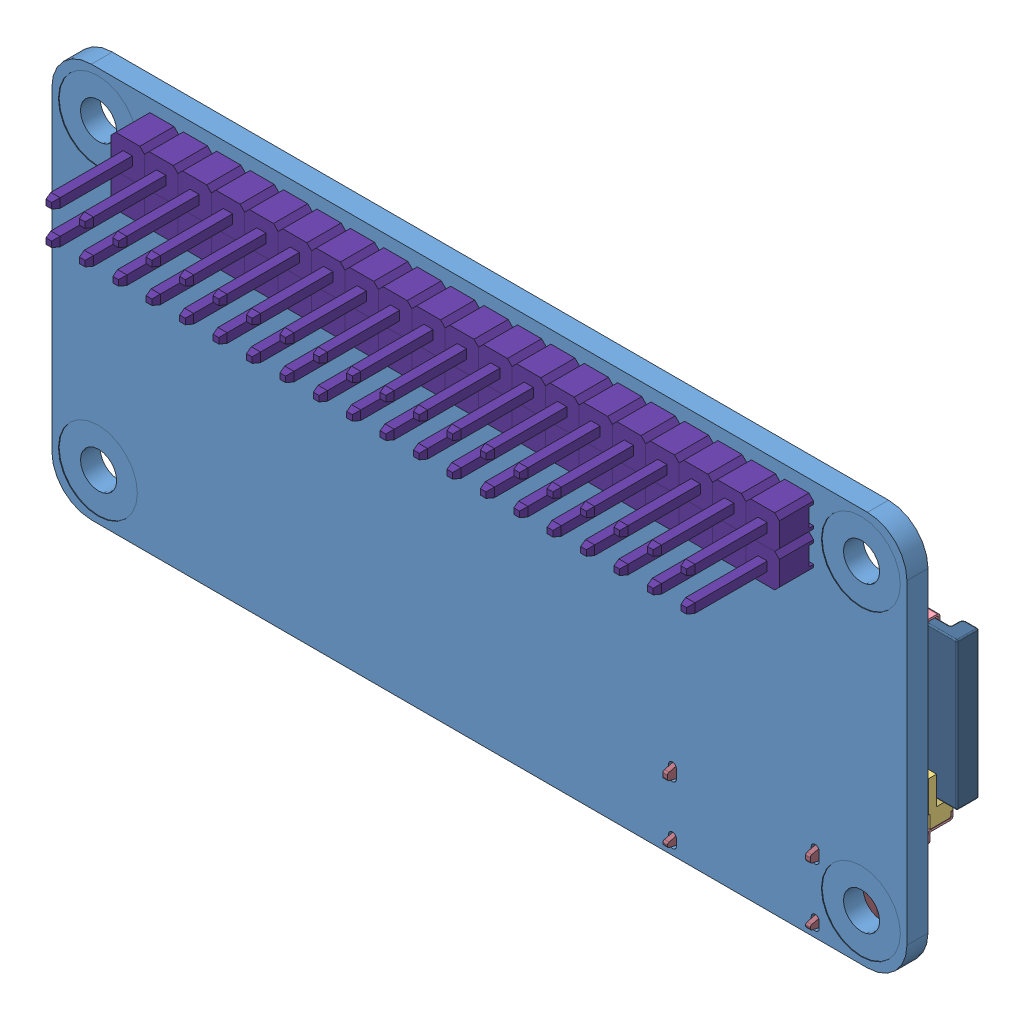
SolidWorks assembly rpi-zero-with-pin-header, configuration Default. Lengths in mm.
Overall size (67.36 31 13.5).
82 component instances, 17 part files, 6 mates.
Components (placement in the parent):
- rpi-zero-1: rpi-zero [Default] at (32.5 -26.5 -2.6) x (-1 0 0) z (0 0 -1) size (67.36 31 5.45)
  - rpi-zero-board-2: rpi-zero-board [Default] at (32.5 15 0) size (65 30 1.65)
  - rpi-zero-pin-header-pad-41: rpi-zero-pin-header-pad [Default] at (8.37 27.77 0.8) size (1.8 1.8 1.7)
  - rpi-zero-micro-sd-slot.step-1: rpi-zero-micro-sd-slot.step [Default] at (7.6 15.665 1.65) x (0 1 0) z (1 0 0) size (14.1 1.9 15.45)
    - microSD_Body.step-1: microSD_Body.step [Default] at origin size (14.1 1.85 15.2)
    - microSD_Cover.step-1: microSD_Cover.step [Default] at (0 1.7 0) x (1 0 0) z (0 0 -1) size (13.95 1.9 15.2)
    - microSD_Card_Detect.step-1: microSD_Card_Detect.step [Default] at (4.99 -0.05 7.4) size (4.45 1.9 2.05)
    - microSD_Pin_11.15.step-1: microSD_Pin_11.15.step [Default] at (5.725 0 -2) x (0 0 1) z (-1 0 0) size (7.35 1.18 0.6)
    - microSD_Pin_11.15.step-2: microSD_Pin_11.15.step [Default] at (4.625 0 -2) x (0 0 1) z (-1 0 0) size (7.35 1.18 0.6)
    - microSD_Pin_11.35.step-1: microSD_Pin_11.35.step [Default] at (3.525 0 -2) x (0 0 1) z (-1 0 0) size (7.35 1.18 0.6)
    - microSD_Pin_11.15.step-3: microSD_Pin_11.15.step [Default] at (2.425 0 -2) x (0 0 1) z (-1 0 0) size (7.35 1.18 0.6)
    - microSD_Pin_11.35.step-2: microSD_Pin_11.35.step [Default] at (1.325 0 -2) x (0 0 1) z (-1 0 0) size (7.35 1.18 0.6)
    - microSD_Pin_11.15.step-4: microSD_Pin_11.15.step [Default] at (0.225 0 -2) x (0 0 1) z (-1 0 0) size (7.35 1.18 0.6)
    - microSD_Pin_10.75.step-1: microSD_Pin_10.75.step [Default] at (-0.875 0 -2) x (0 0 1) z (-1 0 0) size (7.25 1.18 0.6)
    - microSD_Pin_11.15.step-5: microSD_Pin_11.15.step [Default] at (-1.975 0 -2) x (0 0 1) z (-1 0 0) size (7.35 1.18 0.6)
  - rpi-zero-fpc-connector.stp-1: rpi-zero-fpc-connector.stp [Default] at (61.5 15 1.61) x (0 1 0) z (1 0 0) size (17.6 2.04 5.2)
  - rpi-zero-micro-sd.stp-3: rpi-zero-micro-sd.stp [Default] at (6.17 16.9 2.45) x (1 0 0) z (0 -1 0) size (15.06 1.66 11.19)
  - rpi-zero-pin-header-pad-42: rpi-zero-pin-header-pad [Default] at (8.37 25.23 0.8) size (1.8 1.8 1.7)
  - rpi-zero-pin-header-pad-43: rpi-zero-pin-header-pad [Default] at (10.91 27.77 0.8) size (1.8 1.8 1.7)
  - rpi-zero-pin-header-pad-44: rpi-zero-pin-header-pad [Default] at (10.91 25.23 0.8) size (1.8 1.8 1.7)
  - rpi-zero-pin-header-pad-45: rpi-zero-pin-header-pad [Default] at (13.45 27.77 0.8) size (1.8 1.8 1.7)
  - rpi-zero-pin-header-pad-46: rpi-zero-pin-header-pad [Default] at (13.45 25.23 0.8) size (1.8 1.8 1.7)
  - rpi-zero-pin-header-pad-47: rpi-zero-pin-header-pad [Default] at (15.99 27.77 0.8) size (1.8 1.8 1.7)
  - rpi-zero-pin-header-pad-48: rpi-zero-pin-header-pad [Default] at (15.99 25.23 0.8) size (1.8 1.8 1.7)
  - rpi-zero-pin-header-pad-49: rpi-zero-pin-header-pad [Default] at (18.53 27.77 0.8) size (1.8 1.8 1.7)
  - rpi-zero-pin-header-pad-50: rpi-zero-pin-header-pad [Default] at (18.53 25.23 0.8) size (1.8 1.8 1.7)
  - rpi-zero-pin-header-pad-51: rpi-zero-pin-header-pad [Default] at (21.07 27.77 0.8) size (1.8 1.8 1.7)
  - rpi-zero-pin-header-pad-52: rpi-zero-pin-header-pad [Default] at (21.07 25.23 0.8) size (1.8 1.8 1.7)
  - rpi-zero-pin-header-pad-53: rpi-zero-pin-header-pad [Default] at (23.61 27.77 0.8) size (1.8 1.8 1.7)
  - rpi-zero-pin-header-pad-54: rpi-zero-pin-header-pad [Default] at (23.61 25.23 0.8) size (1.8 1.8 1.7)
  - rpi-zero-pin-header-pad-55: rpi-zero-pin-header-pad [Default] at (26.15 27.77 0.8) size (1.8 1.8 1.7)
  - rpi-zero-pin-header-pad-56: rpi-zero-pin-header-pad [Default] at (26.15 25.23 0.8) size (1.8 1.8 1.7)
  - rpi-zero-pin-header-pad-57: rpi-zero-pin-header-pad [Default] at (28.69 27.77 0.8) size (1.8 1.8 1.7)
  - rpi-zero-pin-header-pad-58: rpi-zero-pin-header-pad [Default] at (28.69 25.23 0.8) size (1.8 1.8 1.7)
  - rpi-zero-pin-header-pad-59: rpi-zero-pin-header-pad [Default] at (31.23 27.77 0.8) size (1.8 1.8 1.7)
  - rpi-zero-pin-header-pad-60: rpi-zero-pin-header-pad [Default] at (31.23 25.23 0.8) size (1.8 1.8 1.7)
  - rpi-zero-pin-header-pad-61: rpi-zero-pin-header-pad [Default] at (33.77 27.77 0.8) size (1.8 1.8 1.7)
  - rpi-zero-pin-header-pad-62: rpi-zero-pin-header-pad [Default] at (33.77 25.23 0.8) size (1.8 1.8 1.7)
  - rpi-zero-pin-header-pad-63: rpi-zero-pin-header-pad [Default] at (36.31 27.77 0.8) size (1.8 1.8 1.7)
  - rpi-zero-pin-header-pad-64: rpi-zero-pin-header-pad [Default] at (36.31 25.23 0.8) size (1.8 1.8 1.7)
  - rpi-zero-pin-header-pad-65: rpi-zero-pin-header-pad [Default] at (38.85 27.77 0.8) size (1.8 1.8 1.7)
  - rpi-zero-pin-header-pad-66: rpi-zero-pin-header-pad [Default] at (38.85 25.23 0.8) size (1.8 1.8 1.7)
  - rpi-zero-pin-header-pad-67: rpi-zero-pin-header-pad [Default] at (41.39 27.77 0.8) size (1.8 1.8 1.7)
  - rpi-zero-pin-header-pad-68: rpi-zero-pin-header-pad [Default] at (41.39 25.23 0.8) size (1.8 1.8 1.7)
  - rpi-zero-pin-header-pad-69: rpi-zero-pin-header-pad [Default] at (43.93 27.77 0.8) size (1.8 1.8 1.7)
  - rpi-zero-pin-header-pad-70: rpi-zero-pin-header-pad [Default] at (43.93 25.23 0.8) size (1.8 1.8 1.7)
  - rpi-zero-pin-header-pad-71: rpi-zero-pin-header-pad [Default] at (46.47 27.77 0.8) size (1.8 1.8 1.7)
  - rpi-zero-pin-header-pad-72: rpi-zero-pin-header-pad [Default] at (46.47 25.23 0.8) size (1.8 1.8 1.7)
  - rpi-zero-pin-header-pad-73: rpi-zero-pin-header-pad [Default] at (49.01 27.77 0.8) size (1.8 1.8 1.7)
  - rpi-zero-pin-header-pad-74: rpi-zero-pin-header-pad [Default] at (49.01 25.23 0.8) size (1.8 1.8 1.7)
  - rpi-zero-pin-header-pad-75: rpi-zero-pin-header-pad [Default] at (51.55 27.77 0.8) size (1.8 1.8 1.7)
  - rpi-zero-pin-header-pad-76: rpi-zero-pin-header-pad [Default] at (51.55 25.23 0.8) size (1.8 1.8 1.7)
  - rpi-zero-pin-header-pad-77: rpi-zero-pin-header-pad [Default] at (54.09 27.77 0.8) size (1.8 1.8 1.7)
  - rpi-zero-pin-header-pad-78: rpi-zero-pin-header-pad [Default] at (54.09 25.23 0.8) size (1.8 1.8 1.7)
  - rpi-zero-pin-header-pad-79: rpi-zero-pin-header-pad [Default] at (56.63 27.77 0.8) size (1.8 1.8 1.7)
  - rpi-zero-pin-header-pad-80: rpi-zero-pin-header-pad [Default] at (56.63 25.23 0.8) size (1.8 1.8 1.7)
  - rpi-zero-micro-usb.stp-1: rpi-zero-micro-usb.stp [Default] at (-44 4.3 1.225) x (1 0 0) z (0 -1 0) size (7.91 2.77 5.21)
  - rpi-zero-micro-usb.stp-2: rpi-zero-micro-usb.stp [Default] at (-56.6 4.3 1.225) x (1 0 0) z (0 -1 0) size (7.91 2.77 5.21)
  - rpi-zero-hdmi.stp-1: rpi-zero-hdmi.stp [Default] at (12.4 5.5 3.1) x (0 -1 0) z (0 0 1) size (7.9 11.25 5.45)
    - 685119136923_Housing.stp-1: 685119136923_Housing.stp [Default] at origin size (5.5 11.25 2.9)
    - 685119136923_Shielding.stp-1: 685119136923_Shielding.stp [Default] at (2.875 0 0.82) x (0 1 0) z (0 0 1) size (11.21 7.6 5.45)
    - 685119136923_Housing2.stp-1: 685119136923_Housing2.stp [Default] at (-0.075 0 -0.65) x (0 -1 0) z (0 0 1) size (8.25 0.75 1.6)
    - 685119136923_Pin1.stp-1: 685119136923_Pin1.stp [Default] at (2.1 -3.6 0.3) size (5.9 0.15 1.8)
    - 685119136923_Pin1.stp-2: 685119136923_Pin1.stp [Default] at (2.1 -2.8 0.3) size (5.9 0.15 1.8)
    - 685119136923_Pin1.stp-3: 685119136923_Pin1.stp [Default] at (2.1 -2.4 0.3) size (5.9 0.15 1.8)
    - 685119136923_Pin1.stp-4: 685119136923_Pin1.stp [Default] at (2.1 -2 0.3) size (5.9 0.15 1.8)
    - 685119136923_Pin1.stp-5: 685119136923_Pin1.stp [Default] at (2.1 -1.6 0.3) size (5.9 0.15 1.8)
    - 685119136923_Pin1.stp-6: 685119136923_Pin1.stp [Default] at (2.1 -1.2 0.3) size (5.9 0.15 1.8)
    - 685119136923_Pin1.stp-7: 685119136923_Pin1.stp [Default] at (2.1 -0.8 0.3) size (5.9 0.15 1.8)
    - 685119136923_Pin1.stp-8: 685119136923_Pin1.stp [Default] at (2.1 -0.4 0.3) size (5.9 0.15 1.8)
    - 685119136923_Pin1.stp-9: 685119136923_Pin1.stp [Default] at (2.1 0 0.3) size (5.9 0.15 1.8)
    - 685119136923_Pin1.stp-10: 685119136923_Pin1.stp [Default] at (2.1 0.4 0.3) size (5.9 0.15 1.8)
    - 685119136923_Pin1.stp-11: 685119136923_Pin1.stp [Default] at (2.1 0.8 0.3) size (5.9 0.15 1.8)
    - 685119136923_Pin1.stp-12: 685119136923_Pin1.stp [Default] at (2.1 1.2 0.3) size (5.9 0.15 1.8)
    - 685119136923_Pin1.stp-13: 685119136923_Pin1.stp [Default] at (2.1 1.6 0.3) size (5.9 0.15 1.8)
    - 685119136923_Pin1.stp-14: 685119136923_Pin1.stp [Default] at (2.1 2 0.3) size (5.9 0.15 1.8)
    - 685119136923_Pin1.stp-15: 685119136923_Pin1.stp [Default] at (2.1 2.4 0.3) size (5.9 0.15 1.8)
    - 685119136923_Pin1.stp-16: 685119136923_Pin1.stp [Default] at (2.1 2.8 0.3) size (5.9 0.15 1.8)
    - 685119136923_Pin1.stp-17: 685119136923_Pin1.stp [Default] at (2.1 3.2 0.3) size (5.9 0.15 1.8)
    - 685119136923_Pin1.stp-18: 685119136923_Pin1.stp [Default] at (2.1 3.6 0.3) size (5.9 0.15 1.8)
    - 685119136923_Pin2.stp-1: 685119136923_Pin2.stp [Default] at (1.7983 -3.2 0.3) size (5.3 0.15 1.8)
- rpi-zero-20x2-pin-header-1: rpi-zero-20x2-pin-header [Default] at (0 0 -2.6) size (50.8 5.08 11.6)
Mates (geometry in assembly coordinates):
- Coincident1: coincident anti-aligned: plane of rpi-zero-1/rpi-zero-board-2 through (-29.5 0.5 -2.6) normal (0 0 1); plane of rpi-zero-20x2-pin-header-1 through (-8.89 1.27 -2.6) normal (0 0 -1)
- Coincident2: coincident aligned: plane of rpi-zero-20x2-pin-header-1 through (0 0 -2.6) normal (0 1 0)
- Coincident3: coincident aligned: plane of rpi-zero-20x2-pin-header-1 through (0 0 -2.6) normal (1 0 0)
- Coincident5: coincident aligned: plane of rpi-zero-20x2-pin-header-1 through (24.13 -1.27 0) normal (0 0 1)
- Distance1: distance = 3.5 mm: plane of assembly through (0 0 0) normal (0 1 0); plane of assembly; plane of rpi-zero-1/rpi-zero-board-2 through (29.5 3.5 -4.2) normal (0 1 0)
- Distance2: distance = 32.5 mm: plane of assembly through (0 0 0) normal (1 0 0); plane of assembly; plane of rpi-zero-1/rpi-zero-board-2 through (32.5 0.5 -4.2) normal (1 0 0)
